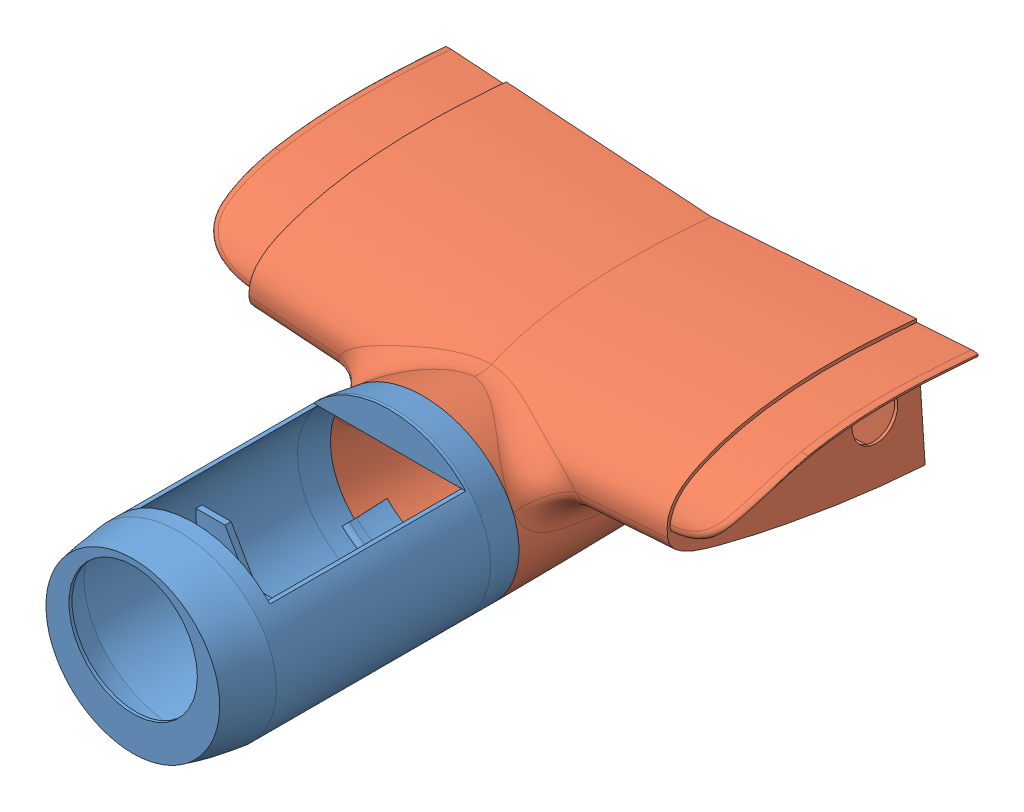
SolidWorks assembly assembled, configuration Default. Lengths in mm.
Overall size (175.34 84.31 199.09).
2 component instances, 2 part files, 3 mates.
Components (placement in the parent):
- fuse_nose-1: fuse_nose [Default] at (-93.59 -8.2512 36.1606) size (66.5 61.66 106.51)
- fuse_mid_front-1: fuse_mid_front [Default] at (-93.59 -8.2516 36.1606) x (1 0 0) z (0 0 1) size (175.34 84.31 109.08)
Mates (geometry in assembly coordinates):
- Coincident1: coincident anti-aligned: plane of fuse_nose-1 through (-93.59 -8.2512 6.1606) normal (0 0 -1); plane of fuse_mid_front-1 through (-93.59 -8.2516 6.1606) normal (0 0 1)
- Coincident2: coincident anti-aligned: line of fuse_nose-1 through (-93.59 -27.5849 6.1606) axis (0 1 0); line of fuse_mid_front-1 through (-93.59 53.5903 6.1606) axis (0 -1 0)
- Coincident4: coincident: point of fuse_nose-1; point of fuse_mid_front-1
